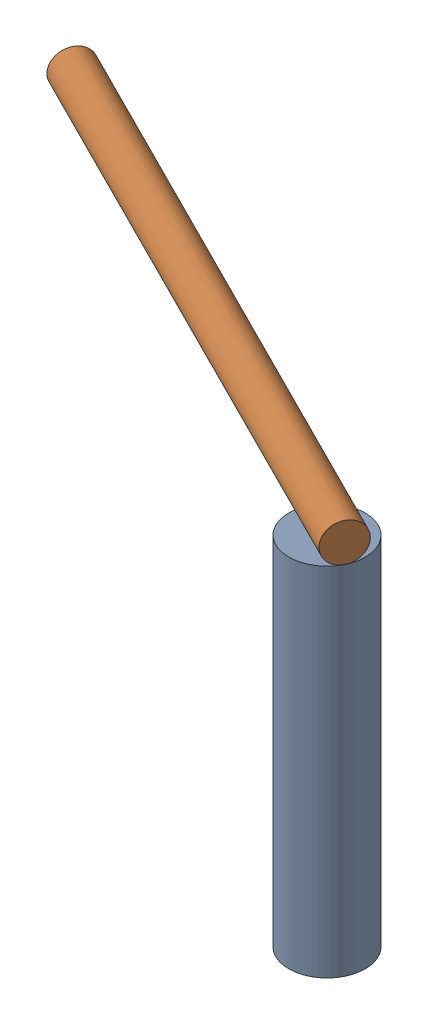
SolidWorks assembly 01-097-00-0, configuration Default. Lengths in mm.
Overall size (141.46 99.52 78.97).
2 component instances, 2 part files, 0 mates.
Components (placement in the parent):
- TROD 0.7500-1x3.5-1: TROD 0.7500-1x3.5 [Default] at origin size (19.05 88.9 19.05)
- 01-096-00-0-1: 01-096-00-0 [Default] at (-127.635 93.6625 -64.2073) x (0.119593 0.96382 -0.238218) z (0.432432 -0.266552 -0.861367) size (9.53 152.4 9.53)
